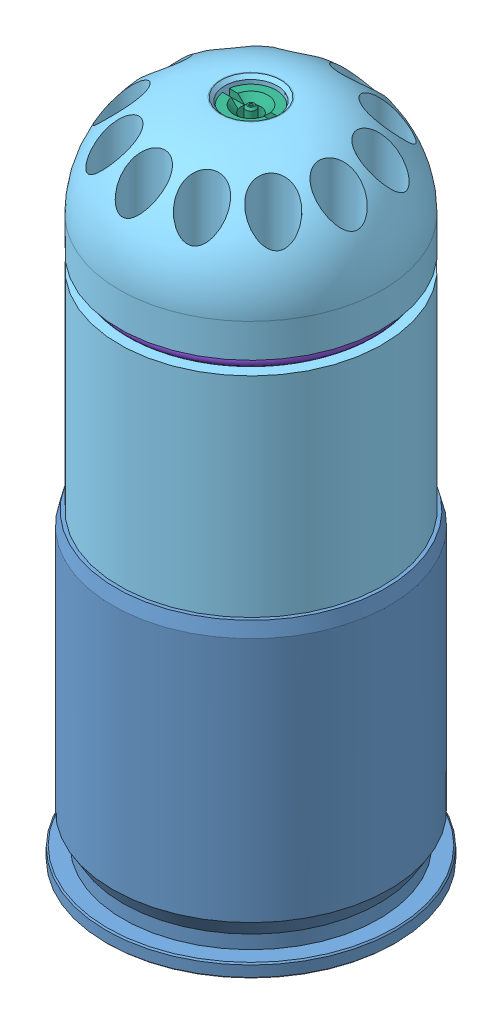
SolidWorks assembly 40mm-Klein, configuration Standard. Lengths in mm.
Overall size (51.21 98 51.21).
11 component instances, 8 part files, 20 mates.
Components (placement in the parent):
- Boden-G-1: Boden-G [Standard] at (-10.8436 -22.8172 45) size (42.9 45 42.9)
- Drücker-G-1: Drücker-G [Standard] at (-10.8436 -22.8172 45) size (14 23 14)
- value-1: value [Standard] at (-10.8436 -4.0172 45) size (20 21.5 20)
- Lock-Kugel-1: Lock-Kugel [Standard] at (-10.8436 -3.0172 55) size (4 4 4)
- Lock-Kugel-2: Lock-Kugel [Standard] at (-0.8436 -3.0172 45) size (4 4 4)
- Lock-Kugel-3: Lock-Kugel [Standard] at (-20.8436 -3.0172 45) size (4 4 4)
- Lock-Kugel-4: Lock-Kugel [Standard] at (-10.8436 -3.0172 35) size (4 4 4)
- Vorn-K-1: Vorn-K [Standard] at (-10.8436 5.6828 45) x (0.99501 0 0.099776) z (-0.099776 0 0.99501) size (39 69.5 39)
- Einfüllventil-1: Einfüllventil [Standard] at (-10.8436 61.6828 45) size (7.5 12.5 7.5)
- value-gegen-1: value-gegen [Standard] at (-10.8436 11.4828 45) x (1 0 -0.000025) z (0.000025 0 1) size (17.5 18.5 17.5)
- O-Ring oben-1: O-Ring oben [Standard] at (-10.8436 54.1828 45) x (-0.837169 0 -0.546944) z (-0.546944 0 0.837169) size (37 2 37)
Mates (geometry in assembly coordinates):
- Konzentrisch1: concentric anti-aligned: cylinder of Boden-G-1 through (-10.8436 -21.8172 45) axis (0 1 0) radius 7; cylinder of Drücker-G-1 through (-10.8436 -12.8172 45) axis (0 -1 0) radius 7
- Deckungsgleich1: coincident aligned: plane of Boden-G-1 through (-10.8436 -22.8172 45) normal (0 -1 0); plane of Drücker-G-1 through (-10.8436 -22.8172 45) normal (0 -1 0)
- Konzentrisch2: concentric: cylinder of value-1 through (-10.8436 -1.0172 35) axis (0 0 1) radius 2; sphere of Lock-Kugel-1
- Tangential2: tangent: curve of value-1; sphere of Lock-Kugel-1
- Konzentrisch3: concentric: cylinder of value-1 through (-20.8436 -1.0172 45) axis (1 0 0) radius 2; sphere of Lock-Kugel-2
- Tangential4: tangent: curve of value-1; sphere of Lock-Kugel-2
- Konzentrisch4: concentric: cylinder of value-1 through (-10.8436 -1.0172 35) axis (0 0 1) radius 2; sphere of Lock-Kugel-4
- Tangential6: tangent: curve of value-1; sphere of Lock-Kugel-4
- Konzentrisch5: concentric: cylinder of value-1 through (-20.8436 -1.0172 45) axis (1 0 0) radius 2; sphere of Lock-Kugel-3
- Tangential8: tangent: curve of value-1; sphere of Lock-Kugel-3
- Deckungsgleich2: coincident aligned: circle of Boden-G-1; cylinder of value-1 through (-10.8436 4.9828 45) axis (0 -1 0) radius 10
- Konzentrisch6: concentric anti-aligned: cylinder of Vorn-K-1 through (-10.8436 5.6828 45) axis (0 1 0) radius 2; cylinder of Einfüllventil-1 through (-10.8436 72.1828 45) axis (0 -1 0) radius 2
- Deckungsgleich3: coincident anti-aligned: plane of Vorn-K-1 through (-10.8436 72.1828 45) normal (0 1 0); plane of Einfüllventil-1 through (-10.8436 72.1828 45) normal (0 -1 0)
- Deckungsgleich4: coincident anti-aligned: plane of Vorn-K-1 through (-10.8436 13.4828 45) normal (0 -1 0); plane of value-gegen-1 through (-10.8436 13.4828 45) normal (0 1 0)
- Konzentrisch7: concentric aligned: cylinder of Vorn-K-1 through (-10.8436 62.6828 45) axis (0 -1 0) radius 7.5; cylinder of value-gegen-1 through (-10.8436 29.9828 45) axis (0 -1 0) radius 7.5
- Deckungsgleich5: coincident anti-aligned: plane of value-1 through (-10.8436 11.4828 45) normal (0 1 0); plane of value-gegen-1 through (-10.8436 11.4828 45) normal (0 -1 0)
- Konzentrisch8: concentric aligned: cylinder of value-1 through (-10.8436 17.4828 45) axis (0 -1 0) radius 4.95; cylinder of value-gegen-1 through (-10.8436 19.2828 45) axis (0 -1 0) radius 5
- Deckungsgleich6: coincident anti-aligned: plane of Boden-G-1 through (-10.8436 22.1828 45) normal (0 1 0); plane of Vorn-K-1 through (-10.8436 22.1828 45) normal (0 -1 0)
- Tangential9: tangent: plane of Vorn-K-1 through (-32.7123 53.1828 42.8071) normal (0 1 0); torus of O-Ring oben-1
- Tangential10: tangent: cylinder of Vorn-K-1 through (-10.8436 75.1828 45) axis (0 1 0) radius 16.5; torus of O-Ring oben-1
